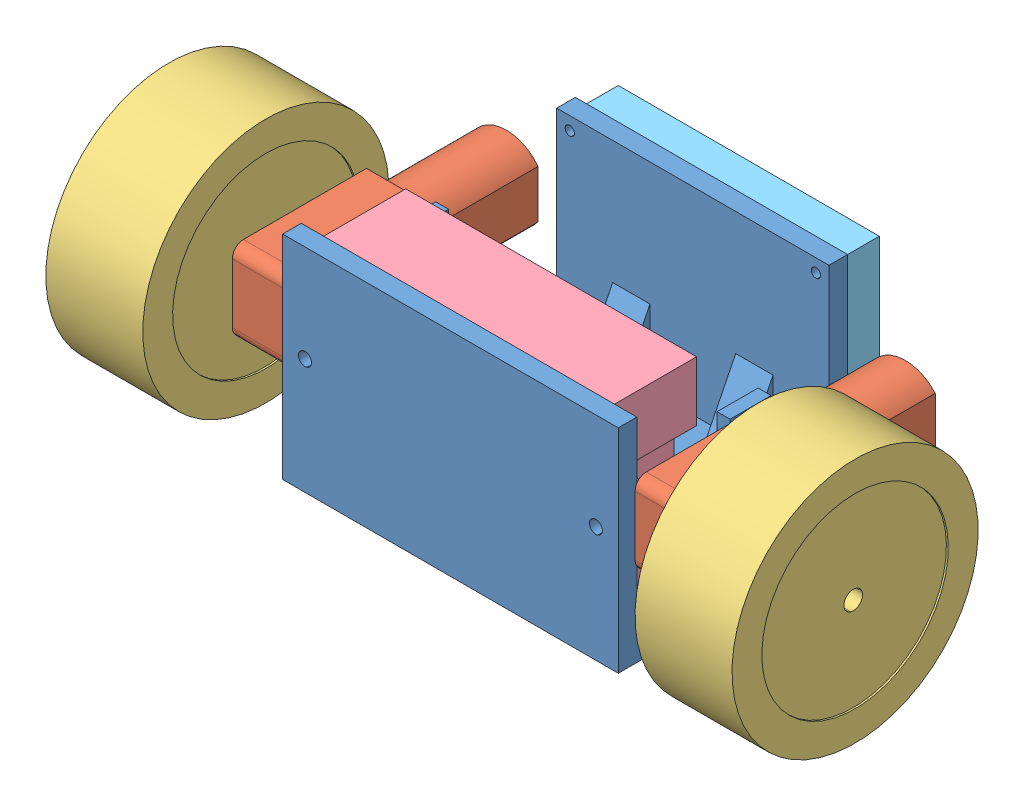
SolidWorks assembly robot_assembly, configuration Default. Lengths in mm.
Overall size (226 93.33 110.17).
7 component instances, 5 part files, 29 mates.
Components (placement in the parent):
- chassis_V1-1: chassis_V1 [Default] at origin size (90 58 70)
- motor-2: motor [Default] at (63 32 12.5) x (0 0 1) z (-1 0 0) size (64 22 26)
- motor-3: motor [Default] at (-63 32 12.5) x (0 0 1) z (1 0 0) size (64 22 26)
- wheel-1: wheel [Default] at (-79 32 18.5) x (0 0.914677 0.404185) z (1 0 0) size (66 66 29)
- wheel-2: wheel [Default] at (79 32 18.5) x (0 -0.71606 0.698038) z (-1 0 0) size (66 66 29)
- battery-1: battery [Default] at (0 31 8) x (1 0 0) z (0 -1 0) size (86 22 52)
- circuit-1: circuit [Default] at (0 31.5 -45) size (70 50 10)
Mates (geometry in assembly coordinates):
- Coincidente3: coincident anti-aligned: plane of chassis_V1-1 through (0 0 0) normal (0 -1 0); plane of Motor_mount-1 through (-41.2805 -26.7418 104.6) normal (0 1 0)
- Coincidente4: coincident anti-aligned: plane of chassis_V1-1 through (-41.2805 -23.7418 100) normal (1 0 0); plane of Motor_mount-1 through (-41.2805 15.0582 99.3) normal (-1 0 0)
- Coincidente5: coincident anti-aligned: plane of chassis_V1-1 through (-12.7805 -23.7418 94) normal (0 0 1); plane of Motor_mount-1 through (-41.2805 15.0582 94) normal (0 0 -1)
- Coincidente6: coincident anti-aligned: plane of chassis_V1-1 through (0 0 0) normal (0 -1 0); plane of Motor_mount-4 through (12.2195 -26.7418 94) normal (0 1 0)
- Coincidente7: coincident anti-aligned: plane of chassis_V1-1 through (36.5 5 0) normal (1 0 0); plane of Motor_mount-4 through (12.2195 15.0582 99.3) normal (-1 0 0)
- Coincidente8: coincident anti-aligned: plane of chassis_V1-1 through (-12.7805 -23.7418 94) normal (0 0 1); plane of Motor_mount-4 through (12.2195 15.0582 94) normal (0 0 -1)
- Coincidente13: coincident anti-aligned: plane of chassis_V1-1 through (0 0 0) normal (0 -1 0); plane of Motor_mount-3 through (-59.2805 -26.7418 94) normal (0 1 0)
- Coincidente14: coincident anti-aligned: plane of chassis_V1-1 through (-12.7805 -23.7418 94) normal (0 0 1); plane of Motor_mount-3 through (-59.2805 15.0582 94) normal (0 0 -1)
- Coincidente15: coincident anti-aligned: plane of chassis_V1-1 through (-59.2805 -23.7418 100) normal (-1 0 0); plane of Motor_mount-3 through (-59.2805 15.0582 99.3) normal (1 0 0)
- Coincidente16: coincident anti-aligned: plane of chassis_V1-1 through (0 0 0) normal (0 -1 0); plane of Motor_mount-2 through (33.7195 -26.7418 104.6) normal (0 1 0)
- Parallelo1: parallel aligned: plane of motor-3 through (-63 32 12.5) normal (-1 0 0); plane of wheel-1 through (-92 32 18.5) normal (-1 0 0)
- Parallelo2: parallel anti-aligned: plane of motor-2 through (45 32 12.5) normal (-1 0 0); plane of wheel-2 through (92 32 18.5) normal (1 0 0)
- Concentrico2: concentric aligned: cylinder of motor-3 through (-71 32 18.5) axis (1 0 0) radius 2.5; cylinder of wheel-1 through (-91.5 32 18.5) axis (1 0 0) radius 2.5
- Coincidente18: coincident anti-aligned: plane of motor-3 through (-63 32 12.5) normal (-1 0 0); plane of wheel-1 through (-63 32 18.5) normal (1 0 0)
- Concentrico3: concentric aligned: cylinder of motor-2 through (71 32 18.5) axis (-1 0 0) radius 2.5; cylinder of wheel-2 through (91.5 32 18.5) axis (-1 0 0) radius 2.5
- Coincidente19: coincident anti-aligned: plane of motor-2 through (63 32 12.5) normal (1 0 0); plane of wheel-2 through (63 32 18.5) normal (-1 0 0)
- Concentrico4: concentric anti-aligned: circle of chassis_V1-1; circle of motor-3
- Concentrico7: concentric aligned: cylinder of chassis_V1-1 through (45 23.5 -0.5) axis (-1 0 0) radius 1.625; cylinder of motor-3 through (-45 23.5 -0.5) axis (-1 0 0) radius 1.5
- Coincidente20: coincident anti-aligned: plane of chassis_V1-1 through (-45 5 0) normal (-1 0 0); plane of motor-3 through (-45 32 12.5) normal (1 0 0)
- Concentrico8: concentric anti-aligned: cylinder of chassis_V1-1 through (45 23.5 -0.5) axis (-1 0 0) radius 1.625; cylinder of motor-2 through (45 23.5 -0.5) axis (1 0 0) radius 1.5
- Concentrico9: concentric anti-aligned: cylinder of chassis_V1-1 through (45 40.5 -0.5) axis (-1 0 0) radius 1.625; cylinder of motor-2 through (45 40.5 -0.5) axis (1 0 0) radius 1.5
- Coincidente21: coincident anti-aligned: plane of chassis_V1-1 through (45 5 0) normal (1 0 0); plane of motor-2 through (45 32 12.5) normal (-1 0 0)
- Coincidente22: coincident anti-aligned: plane of chassis_V1-1 through (0 57 30) normal (0 0 -1); plane of battery-1 through (0 31 30) normal (0 0 1)
- Concentrico13: concentric anti-aligned: circle of chassis_V1-1; circle of circuit-1
- Concentrico12: concentric anti-aligned: circle of chassis_V1-1; circle of circuit-1
- Coincidente27: coincident anti-aligned: plane of chassis_V1-1 through (0 5 -35) normal (0 0 -1); plane of circuit-1 through (0 31.5 -35) normal (0 0 1)
- Concentrico14: concentric aligned: circle of chassis_V1-1; circle of battery-1
- Concentrico15: concentric anti-aligned: circle of chassis_V1-1; circle of battery-1
- Coincidente30: coordinate: unknown of chassis_V1-1
